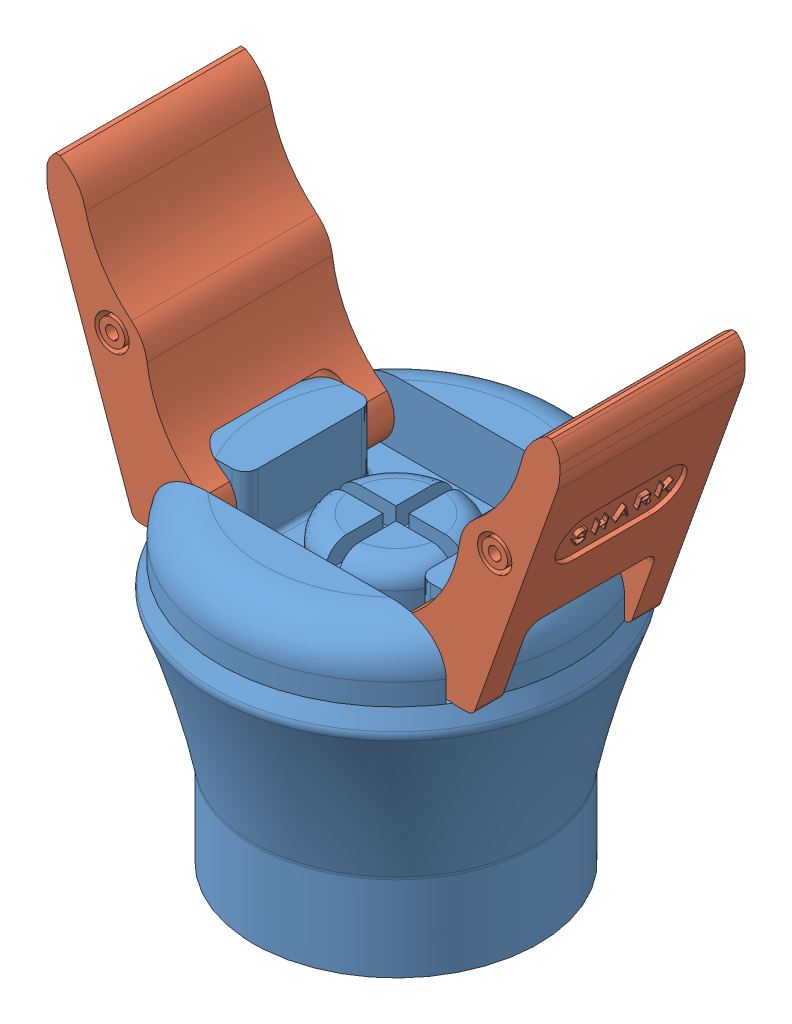
SolidWorks assembly end_effector, configuration 默认. Lengths in mm.
Overall size (118.98 124.39 85.45).
3 component instances, 2 part files, 7 mates.
Components (placement in the parent):
- tool_link-1: tool_link [默认] at origin size (85.45 76.02 85.45)
- finger_link-1: finger_link [默认] at (-39.3817 59.864 0) size (37.61 64.53 43)
- finger_link-2: finger_link [默认] at (39.3817 59.864 0) x (-1 0 0) z (0 0 -1) size (37.61 64.53 43)
Mates (geometry in assembly coordinates):
- 同心1: concentric anti-aligned: cylinder of tool_link-1 through (-29.3817 67.364 -42.724) axis (0 0 1) radius 5; cylinder of finger_link-1 through (-29.3817 67.364 15) axis (0 0 -1) radius 5
- 重合1: coincident anti-aligned: plane of tool_link-1 through (-38.0178 75 -15) normal (0 0 -1); plane of finger_link-1 through (-59.4895 77.864 -15) normal (0 0 1)
- 同心2: concentric aligned: cylinder of tool_link-1 through (29.3817 67.364 -42.724) axis (0 0 1) radius 5; cylinder of finger_link-2 through (29.3817 67.364 -15) axis (0 0 1) radius 5
- 重合2: coincident anti-aligned: plane of tool_link-1 through (23.0178 75 15) normal (0 0 1); plane of finger_link-2 through (59.4895 77.864 15) normal (0 0 -1)
- 重合5: coordinate: point of tool_link-1
- 平行3: parallel anti-aligned: plane of tool_link-1 through (44.7229 60 0) normal (0 1 0); plane of finger_link-2 through (39.3817 59.864 -21.5) normal (0 -1 0)
- 平行4: parallel anti-aligned: plane of tool_link-1 through (44.7229 60 0) normal (0 1 0); plane of finger_link-1 through (-39.3817 59.864 21.5) normal (0 -1 0)
